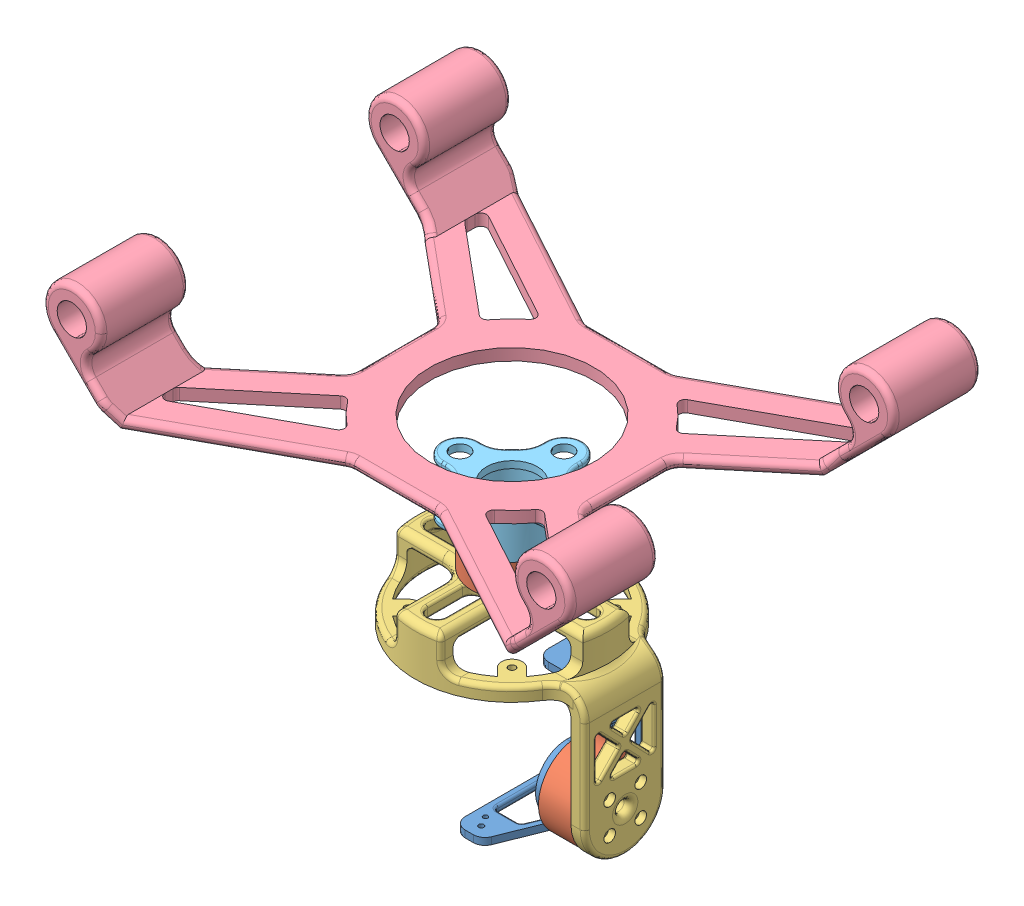
SolidWorks assembly assembly, configuration Default. Lengths in mm.
Overall size (228.6 190.88 177.8).
7 component instances, 6 part files, 14 mates.
Components (placement in the parent):
- cameraBracket-1: cameraBracket [Default] at origin size (34.01 49 55)
- motor-1: motor [Default] at (15.3923 -20.5 15) x (1 0 0) z (0 -0.863303 0.504685) size (14.3 34.5 34.5)
- panBracket-1: panBracket [Default] at (29.6923 -20.5 15) size (90.84 83.7 83.67)
- motor-2: motor [Default] at (-13.3077 45.5 15) x (0 1 0) z (0 0 1) size (14.3 34.5 34.5)
- vibrationDampenerRing-1: vibrationDampenerRing [Default] at (-13.3077 55.5 15) size (119.3 20.84 106.17) (hidden)
- jaguarCameraBracket-1: jaguarCameraBracket [Default] at (-13.3077 106.7803 15) size (228.6 47.08 177.8)
- slipRingMountV2-1: slipRingMountV2 [Default] at (-13.3077 59.8 15) size (61 18 61)
Mates (geometry in assembly coordinates):
- Concentric1: concentric anti-aligned: circle of cameraBracket-1; circle of motor-1
- Coincident1: coincident anti-aligned: plane of cameraBracket-1 through (15.3923 -20.5 15) normal (1 0 0); plane of motor-1 through (15.3923 -20.5 15) normal (-1 0 0)
- Concentric2: concentric aligned: circle of motor-1; circle of panBracket-1
- Coincident2: coincident anti-aligned: plane of motor-1 through (29.6923 -20.5 15) normal (1 0 0); plane of panBracket-1 through (29.6923 -20.5 15) normal (-1 0 0)
- Coincident3: coincident anti-aligned: plane of panBracket-1 through (-13.3077 45.5 15) normal (0 1 0); plane of motor-2 through (-13.3077 45.5 15) normal (0 -1 0)
- Concentric3: concentric anti-aligned: circle of panBracket-1; circle of motor-2
- Coincident4: coincident anti-aligned: plane of motor-2 through (-13.3077 59.8 15) normal (0 1 0); plane of slipRingMount-1 through (-13.3077 59.8 15) normal (0 -1 0)
- Concentric4: concentric aligned: circle of motor-2; circle of slipRingMount-1
- Concentric5: concentric aligned: circle of slipRingMount-1; circle of vibrationDampenerRing-1
- Distance1: distance = 10 mm anti-aligned: plane of vibrationDampenerRing-1 through (-13.3077 55.5 15) normal (0 -1 0); plane of panBracket-1 through (-13.3077 45.5 15) normal (0 1 0)
- Concentric6: concentric aligned: circle of slipRingMount-1; circle of jaguarCameraBracket-1
- Distance2: distance = 20 mm anti-aligned: plane of slipRingMount-1 through (-13.3077 77.8 15) normal (0 1 0); plane of jaguarCameraBracket-1 through (-98.4879 97.8 -296.5143) normal (0 -1 0)
- Coincident5: coincident anti-aligned: plane of motor-2 through (-13.3077 59.8 15) normal (0 1 0); plane of slipRingMountV2-1 through (-13.3077 59.8 15) normal (0 -1 0)
- Concentric7: concentric aligned: circle of motor-2; circle of slipRingMountV2-1
